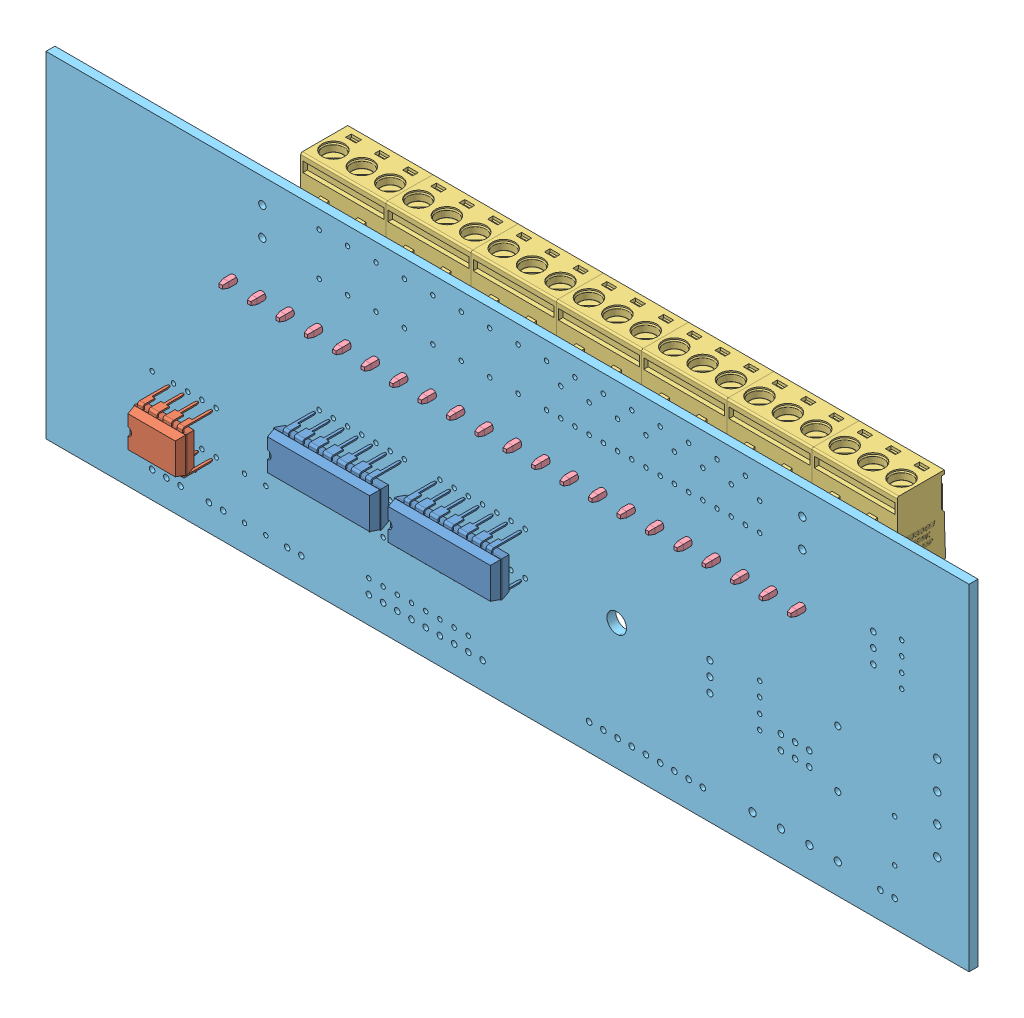
SolidWorks assembly minilab, configuration Predeterminado. Lengths in mm.
Overall size (165 60 30.78).
35 component instances, 5 part files, 0 mates.
Components (placement in the parent):
- DIP-14_W7.62mm-1: DIP-14_W7.62mm [Predeterminado] at (106.675 -110.48 5.65) x (0 1 0) z (0 0 1) size (7.87 19.05 6.98)
  - SOLID-1: SOLID [Predeterminado] at origin size (7.87 19.05 6.98)
- DIP-8_W7.62mm-1: DIP-8_W7.62mm [Predeterminado] at (80.645 -119.38 5.65) x (0 1 0) z (0 0 1) size (7.87 9.27 6.98)
  - SOLID_2-1: SOLID_2 [Predeterminado] at origin size (7.87 9.27 6.98)
- DIP-14_W7.62mm-2: DIP-14_W7.62mm [Predeterminado] at (128.27 -110.48 5.65) x (0 1 0) z (0 0 1) size (7.87 19.05 6.98)
  - SOLID-1: SOLID [Predeterminado] at origin size (7.87 19.05 6.98)
- 2EDGK-5.08-03P-14-00AH-1: 2EDGK-5.08-03P-14-00AH [Predeterminado] at (104.14 -94.21 -4.05) x (1 0 0) z (0 1 0) size (15.24 17.4 15.1)
  - SOLID_3-1: SOLID_3 [Predeterminado] at origin size (15.24 17.4 15.1)
- 2EDGV-5.08-03P-14-00AH-1: 2EDGV-5.08-03P-14-00AH [Predeterminado] at (104.14 -93.91 -0.05) x (1 0 0) z (0 1 0) size (15.24 16.1 8.2)
  - SOLID_4-1: SOLID_4 [Predeterminado] at origin size (15.24 16.1 8.2)
- 2EDGK-5.08-03P-14-00AH-2: 2EDGK-5.08-03P-14-00AH [Predeterminado] at (134.62 -94.21 -4.05) x (1 0 0) z (0 1 0) size (15.24 17.4 15.1)
  - SOLID_3-1: SOLID_3 [Predeterminado] at origin size (15.24 17.4 15.1)
- 2EDGV-5.08-03P-14-00AH-2: 2EDGV-5.08-03P-14-00AH [Predeterminado] at (134.62 -93.91 -0.05) x (1 0 0) z (0 1 0) size (15.24 16.1 8.2)
  - SOLID_4-1: SOLID_4 [Predeterminado] at origin size (15.24 16.1 8.2)
- 2EDGK-5.08-03P-14-00AH-3: 2EDGK-5.08-03P-14-00AH [Predeterminado] at (149.86 -94.21 -4.05) x (1 0 0) z (0 1 0) size (15.24 17.4 15.1)
  - SOLID_3-1: SOLID_3 [Predeterminado] at origin size (15.24 17.4 15.1)
- 2EDGV-5.08-03P-14-00AH-3: 2EDGV-5.08-03P-14-00AH [Predeterminado] at (149.86 -93.91 -0.05) x (1 0 0) z (0 1 0) size (15.24 16.1 8.2)
  - SOLID_4-1: SOLID_4 [Predeterminado] at origin size (15.24 16.1 8.2)
- 2EDGK-5.08-03P-14-00AH-4: 2EDGK-5.08-03P-14-00AH [Predeterminado] at (165.1 -94.21 -4.05) x (1 0 0) z (0 1 0) size (15.24 17.4 15.1)
  - SOLID_3-1: SOLID_3 [Predeterminado] at origin size (15.24 17.4 15.1)
- 2EDGV-5.08-03P-14-00AH-4: 2EDGV-5.08-03P-14-00AH [Predeterminado] at (165.1 -93.91 -0.05) x (1 0 0) z (0 1 0) size (15.24 16.1 8.2)
  - SOLID_4-1: SOLID_4 [Predeterminado] at origin size (15.24 16.1 8.2)
- 2EDGK-5.08-03P-14-00AH-5: 2EDGK-5.08-03P-14-00AH [Predeterminado] at (180.34 -94.21 -4.05) x (1 0 0) z (0 1 0) size (15.24 17.4 15.1)
  - SOLID_3-1: SOLID_3 [Predeterminado] at origin size (15.24 17.4 15.1)
- 2EDGV-5.08-03P-14-00AH-5: 2EDGV-5.08-03P-14-00AH [Predeterminado] at (180.34 -93.91 -0.05) x (1 0 0) z (0 1 0) size (15.24 16.1 8.2)
  - SOLID_4-1: SOLID_4 [Predeterminado] at origin size (15.24 16.1 8.2)
- 2EDGK-5.08-03P-14-00AH-6: 2EDGK-5.08-03P-14-00AH [Predeterminado] at (119.38 -94.21 -4.05) x (1 0 0) z (0 1 0) size (15.24 17.4 15.1)
  - SOLID_3-1: SOLID_3 [Predeterminado] at origin size (15.24 17.4 15.1)
- 2EDGV-5.08-03P-14-00AH-6: 2EDGV-5.08-03P-14-00AH [Predeterminado] at (119.38 -93.91 -0.05) x (1 0 0) z (0 1 0) size (15.24 16.1 8.2)
  - SOLID_4-1: SOLID_4 [Predeterminado] at origin size (15.24 16.1 8.2)
- 2EDGK-5.08-03P-14-00AH-7: 2EDGK-5.08-03P-14-00AH [Predeterminado] at (88.94 -94.21 -4.05) x (1 0 0) z (0 1 0) size (15.24 17.4 15.1)
  - SOLID_3-1: SOLID_3 [Predeterminado] at origin size (15.24 17.4 15.1)
- 2EDGV-5.08-03P-14-00AH-7: 2EDGV-5.08-03P-14-00AH [Predeterminado] at (88.9 -93.91 -0.05) x (1 0 0) z (0 1 0) size (15.24 16.1 8.2)
  - SOLID_4-1: SOLID_4 [Predeterminado] at origin size (15.24 16.1 8.2)
- minilab PCB-1: minilab PCB [Predeterminado] at origin size (165 60 1.6)
